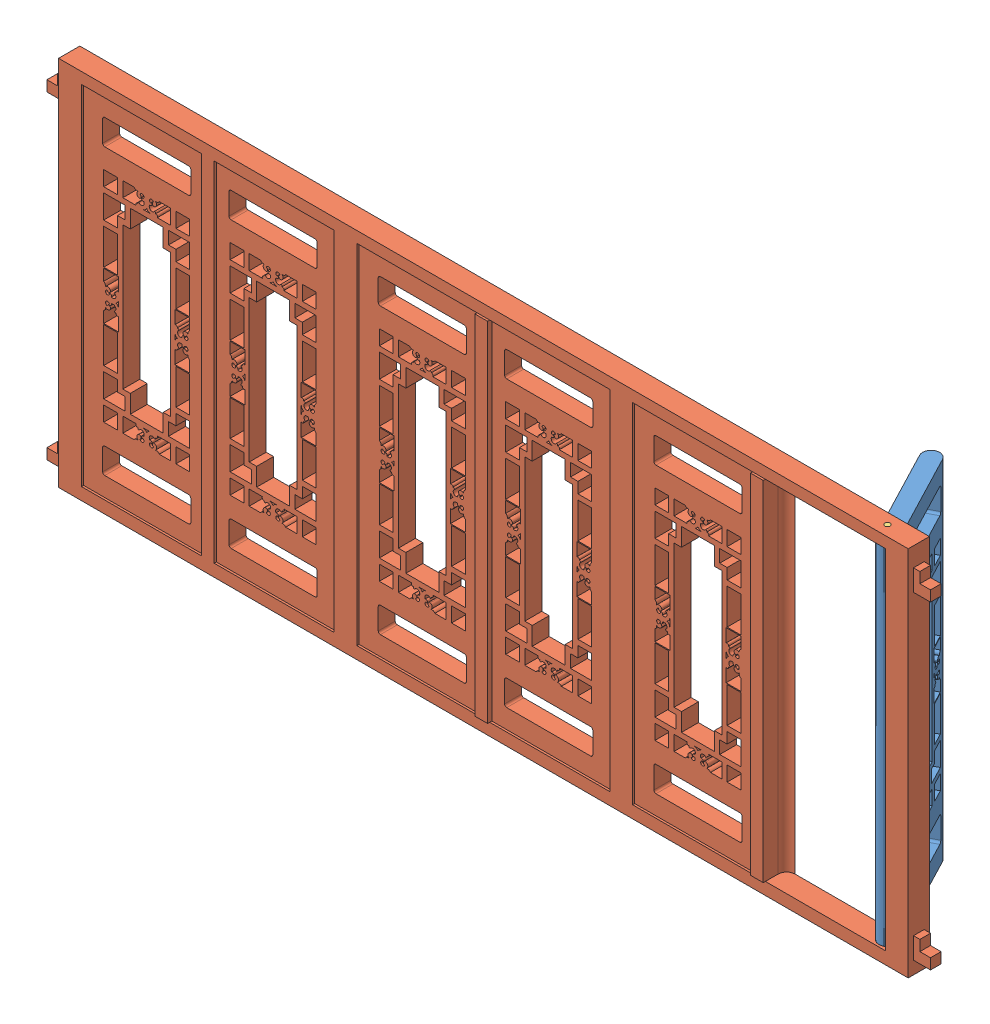
SolidWorks assembly 窗户装配, configuration 默认. Lengths in mm.
Overall size (4160 1750 543.88).
3 component instances, 3 part files, 5 mates.
Components (placement in the parent):
- 二楼窗户单个-1: 二楼窗户单个 [默认] at (-286.4472 -721.554 1738.9724) x (-0.462898 0 -0.886412) z (0.886412 0 -0.462898) size (565 1690 80)
- 二楼窗户合3-1: 二楼窗户合3 [默认] at (-4014.5067 -721.554 1645) size (4160 1750 110)
- 窗户销-1: 窗户销 [默认] at (-269.5067 -779.054 1685) size (25 1750 25)
Mates (geometry in assembly coordinates):
- 同心1: concentric: cylinder of 二楼窗户单个-1 through (-269.5067 -746.554 1685) axis (0 1 0) radius 12.5; cylinder of 窗户销-1 through (-269.5067 970.946 1685) axis (0 -1 0) radius 12.5
- 重合2: coincident: plane of 二楼窗户合3-1 through (-2824.5067 970.946 1635) normal (0 1 0); plane of 窗户销-1 through (-269.5067 970.946 1685) normal (0 1 0)
- 同心2: concentric: cylinder of 二楼窗户单个-1 through (-269.5067 943.446 1685) axis (0 -1 0) radius 25; cylinder of 二楼窗户合3-1 through (-269.5067 943.446 1685) axis (0 -1 0) radius 25
- 重合3: coincident: plane of 二楼窗户单个-1 through (-269.5067 943.446 1685) normal (0 1 0); plane of 二楼窗户合3-1 through (-269.5067 943.446 1685) normal (0 -1 0)
- LimitAngle1: limit planar angle = 0.481262 rad: plane of 二楼窗户单个-1 through (-286.4472 -721.554 1738.9724) normal (-0.886412 0 0.462898); plane of 二楼窗户合3-1 through (-229.5067 918.446 1635) normal (-1 0 0)
